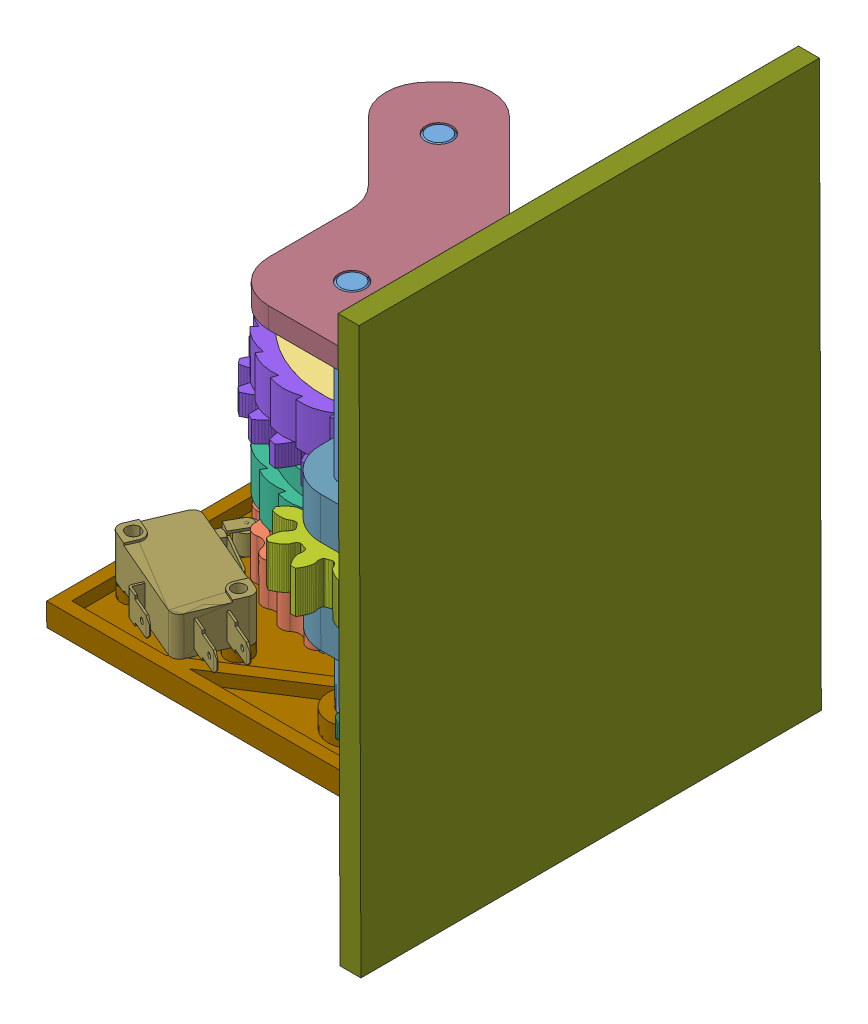
SolidWorks assembly Partially open assembly, configuration Default. Lengths in mm.
Overall size (104.96 135.58 125.24).
121 component instances, 25 part files, 36 mates.
Components (placement in the parent):
- Mounting bar-1: Mounting bar [Default] at (-40 -130.3709 9.0195) x (0.975852 0.000746 -0.218429) z (0.218431 -0.003332 0.975847) size (6.35 101.6 6.35)
- Mounting bar-2: Mounting bar [Default] at (-19.9279 -130.5102 49.7998) x (-0.610818 0.002704 -0.791767) z (0.791771 0.002086 -0.610814) size (6.35 101.6 6.35)
- Battery 9V-1: Battery 9V [Default] at (-16.7556 -79.5866 69.2456) x (1 0 0.000033) z (0.000033 0.003415 -0.999994) size (25.91 48.13 16.26) (hidden)
- Letter selection wheel assembly-1: Letter selection wheel assembly [Default] at (-83.764 -141.894 -21.2692) x (0.903739 0.001462 -0.428081) z (0.428084 -0.003086 0.903734) size (72.37 17.5 74.83)
  - Letter selection wheel-1: Letter selection wheel [Default] at (26.602 23.0199 46.072) size (64.18 15 64.19)
  - PCB assembly-1: PCB assembly [Default] at (20.8498 33.5038 101.5951) x (1 0 0) z (0 1 0) size (67.78 70.24 3.5)
    - selector wheel PCB-2: selector wheel PCB [Default] at (5.7522 55.5231 3.5161) size (67.78 70.24 1)
    - spring pin-27: spring pin [Default] at (7.3927 81.0239 5.3161) x (1 0 0) z (0 -1 0) size (3.66 2.5 0.96)
    - spring pin-28: spring pin [Default] at (1.2423 80.6755 5.3161) x (0.970942 0.239316 0) z (0.239316 -0.970942 0) size (3.66 2.5 0.96)
    - spring pin-29: spring pin [Default] at (-4.6461 78.8653 5.3161) x (0.885456 0.464723 0) z (0.464723 -0.885456 0) size (3.66 2.5 0.96)
    - spring pin-30: spring pin [Default] at (-9.9301 75.6986 5.3161) x (0.748511 0.663123 0) z (0.663123 -0.748511 0) size (3.66 2.5 0.96)
    - spring pin-31: spring pin [Default] at (-14.3027 71.3593 5.3161) x (0.568065 0.822984 0) z (0.822984 -0.568065 0) size (3.66 2.5 0.96)
    - spring pin-32: spring pin [Default] at (-17.5098 66.0997 5.3161) x (0.354605 0.935016 0) z (0.935016 -0.354605 0) size (3.66 2.5 0.96)
    - spring pin-33: spring pin [Default] at (-19.365 60.2254 5.3161) x (0.120537 0.992709 0) z (0.992709 -0.120537 0) size (3.66 2.5 0.96)
    - spring pin-34: spring pin [Default] at (-19.7605 54.0778 5.3161) x (-0.120537 0.992709 0) z (0.992709 0.120537 0) size (3.66 2.5 0.96)
    - spring pin-35: spring pin [Default] at (-18.6732 48.0142 5.3161) x (-0.354605 0.935016 0) z (0.935016 0.354605 0) size (3.66 2.5 0.96)
    - spring pin-36: spring pin [Default] at (-16.1665 42.3871 5.3161) x (-0.568065 0.822984 0) z (0.822984 0.568065 0) size (3.66 2.5 0.96)
    - spring pin-37: spring pin [Default] at (-12.3859 37.5233 5.3161) x (-0.748511 0.663123 0) z (0.663123 0.748511 0) size (3.66 2.5 0.96)
    - spring pin-38: spring pin [Default] at (-7.5512 33.7056 5.3161) x (-0.885456 0.464723 0) z (0.464723 0.885456 0) size (3.66 2.5 0.96)
    - spring pin-39: spring pin [Default] at (-1.9434 31.1559 5.3161) x (-0.970942 0.239316 0) z (0.239316 0.970942 0) size (3.66 2.5 0.96)
    - spring pin-40: spring pin [Default] at (4.1117 30.0223 5.3161) x (-1 0 0) z (0 1 0) size (3.66 2.5 0.96)
    - spring pin-41: spring pin [Default] at (10.2621 30.3707 5.3161) x (-0.970942 -0.239316 0) z (-0.239316 0.970942 0) size (3.66 2.5 0.96)
    - spring pin-42: spring pin [Default] at (16.1505 32.1809 5.3161) x (-0.885456 -0.464723 0) z (-0.464723 0.885456 0) size (3.66 2.5 0.96)
    - spring pin-43: spring pin [Default] at (21.4345 35.3476 5.3161) x (-0.748511 -0.663123 0) z (-0.663123 0.748511 0) size (3.66 2.5 0.96)
    - spring pin-44: spring pin [Default] at (25.8071 39.6869 5.3161) x (-0.568065 -0.822984 0) z (-0.822984 0.568065 0) size (3.66 2.5 0.96)
    - spring pin-45: spring pin [Default] at (29.0142 44.9465 5.3161) x (-0.354605 -0.935016 0) z (-0.935016 0.354605 0) size (3.66 2.5 0.96)
    - spring pin-46: spring pin [Default] at (30.8694 50.8208 5.3161) x (-0.120537 -0.992709 0) z (-0.992709 0.120537 0) size (3.66 2.5 0.96)
    - spring pin-47: spring pin [Default] at (31.2649 56.9684 5.3161) x (0.120537 -0.992709 0) z (-0.992709 -0.120537 0) size (3.66 2.5 0.96)
    - spring pin-48: spring pin [Default] at (30.1776 63.032 5.3161) x (0.354605 -0.935016 0) z (-0.935016 -0.354605 0) size (3.66 2.5 0.96)
    - spring pin-49: spring pin [Default] at (27.6709 68.6591 5.3161) x (0.568065 -0.822984 0) z (-0.822984 -0.568065 0) size (3.66 2.5 0.96)
    - spring pin-50: spring pin [Default] at (23.8903 73.5229 5.3161) x (0.748511 -0.663123 0) z (-0.663123 -0.748511 0) size (3.66 2.5 0.96)
    - spring pin-51: spring pin [Default] at (19.0556 77.3406 5.3161) x (0.885456 -0.464723 0) z (-0.464723 -0.885456 0) size (3.66 2.5 0.96)
    - spring pin-52: spring pin [Default] at (13.4478 79.8903 5.3161) x (0.970942 -0.239316 0) z (-0.239316 -0.970942 0) size (3.66 2.5 0.96)
  - selector wheel PCB-3: selector wheel PCB [Default] at (26.602 23.0199 46.072) x (1 0 0) z (0 1 0) size (67.78 70.24 1)
  - 57155K356 ball bearing-1: 57155K356 ball bearing [57155K356] at (26.602 31.4324 46.072) x (1 0 0) z (0 -1 0) size (12.7 12.7 3.17)
- Scrambler wheel assembly-1: Scrambler wheel assembly [Default] at (-30.9853 -125.6197 -45.8761) x (0.827018 -0.00192 0.562173) z (-0.562176 -0.002824 0.827013) size (72.54 17.5 74.67)
  - Scrambler wheel-1: Scrambler wheel [Default] at (23.4146 24.3298 50.4806) size (65.8 15 63.85)
  - PCB assembly-1: PCB assembly [Default] at (17.9086 34.8137 106.1338) x (1 0 0) z (0 1 0) size (67.78 70.24 3.5)
    - selector wheel PCB-2: selector wheel PCB [Default] at (5.7522 55.5231 3.5161) size (67.78 70.24 1)
    - spring pin-27: spring pin [Default] at (7.3927 81.0239 5.3161) x (1 0 0) z (0 -1 0) size (3.66 2.5 0.96)
    - spring pin-28: spring pin [Default] at (1.2423 80.6755 5.3161) x (0.970942 0.239316 0) z (0.239316 -0.970942 0) size (3.66 2.5 0.96)
    - spring pin-29: spring pin [Default] at (-4.6461 78.8653 5.3161) x (0.885456 0.464723 0) z (0.464723 -0.885456 0) size (3.66 2.5 0.96)
    - spring pin-30: spring pin [Default] at (-9.9301 75.6986 5.3161) x (0.748511 0.663123 0) z (0.663123 -0.748511 0) size (3.66 2.5 0.96)
    - spring pin-31: spring pin [Default] at (-14.3027 71.3593 5.3161) x (0.568065 0.822984 0) z (0.822984 -0.568065 0) size (3.66 2.5 0.96)
    - spring pin-32: spring pin [Default] at (-17.5098 66.0997 5.3161) x (0.354605 0.935016 0) z (0.935016 -0.354605 0) size (3.66 2.5 0.96)
    - spring pin-33: spring pin [Default] at (-19.365 60.2254 5.3161) x (0.120537 0.992709 0) z (0.992709 -0.120537 0) size (3.66 2.5 0.96)
    - spring pin-34: spring pin [Default] at (-19.7605 54.0778 5.3161) x (-0.120537 0.992709 0) z (0.992709 0.120537 0) size (3.66 2.5 0.96)
    - spring pin-35: spring pin [Default] at (-18.6732 48.0142 5.3161) x (-0.354605 0.935016 0) z (0.935016 0.354605 0) size (3.66 2.5 0.96)
    - spring pin-36: spring pin [Default] at (-16.1665 42.3871 5.3161) x (-0.568065 0.822984 0) z (0.822984 0.568065 0) size (3.66 2.5 0.96)
    - spring pin-37: spring pin [Default] at (-12.3859 37.5233 5.3161) x (-0.748511 0.663123 0) z (0.663123 0.748511 0) size (3.66 2.5 0.96)
    - spring pin-38: spring pin [Default] at (-7.5512 33.7056 5.3161) x (-0.885456 0.464723 0) z (0.464723 0.885456 0) size (3.66 2.5 0.96)
    - spring pin-39: spring pin [Default] at (-1.9434 31.1559 5.3161) x (-0.970942 0.239316 0) z (0.239316 0.970942 0) size (3.66 2.5 0.96)
    - spring pin-40: spring pin [Default] at (4.1117 30.0223 5.3161) x (-1 0 0) z (0 1 0) size (3.66 2.5 0.96)
    - spring pin-41: spring pin [Default] at (10.2621 30.3707 5.3161) x (-0.970942 -0.239316 0) z (-0.239316 0.970942 0) size (3.66 2.5 0.96)
    - spring pin-42: spring pin [Default] at (16.1505 32.1809 5.3161) x (-0.885456 -0.464723 0) z (-0.464723 0.885456 0) size (3.66 2.5 0.96)
    - spring pin-43: spring pin [Default] at (21.4345 35.3476 5.3161) x (-0.748511 -0.663123 0) z (-0.663123 0.748511 0) size (3.66 2.5 0.96)
    - spring pin-44: spring pin [Default] at (25.8071 39.6869 5.3161) x (-0.568065 -0.822984 0) z (-0.822984 0.568065 0) size (3.66 2.5 0.96)
    - spring pin-45: spring pin [Default] at (29.0142 44.9465 5.3161) x (-0.354605 -0.935016 0) z (-0.935016 0.354605 0) size (3.66 2.5 0.96)
    - spring pin-46: spring pin [Default] at (30.8694 50.8208 5.3161) x (-0.120537 -0.992709 0) z (-0.992709 0.120537 0) size (3.66 2.5 0.96)
    - spring pin-47: spring pin [Default] at (31.2649 56.9684 5.3161) x (0.120537 -0.992709 0) z (-0.992709 -0.120537 0) size (3.66 2.5 0.96)
    - spring pin-48: spring pin [Default] at (30.1776 63.032 5.3161) x (0.354605 -0.935016 0) z (-0.935016 -0.354605 0) size (3.66 2.5 0.96)
    - spring pin-49: spring pin [Default] at (27.6709 68.6591 5.3161) x (0.568065 -0.822984 0) z (-0.822984 -0.568065 0) size (3.66 2.5 0.96)
    - spring pin-50: spring pin [Default] at (23.8903 73.5229 5.3161) x (0.748511 -0.663123 0) z (-0.663123 -0.748511 0) size (3.66 2.5 0.96)
    - spring pin-51: spring pin [Default] at (19.0556 77.3406 5.3161) x (0.885456 -0.464723 0) z (-0.464723 -0.885456 0) size (3.66 2.5 0.96)
    - spring pin-52: spring pin [Default] at (13.4478 79.8903 5.3161) x (0.970942 -0.239316 0) z (-0.239316 -0.970942 0) size (3.66 2.5 0.96)
  - selector wheel PCB-1: selector wheel PCB [Default] at (23.4146 24.3298 50.4806) x (1 0 0) z (0 1 0) size (67.78 70.24 1)
  - 57155K356 ball bearing-1: 57155K356 ball bearing [57155K356] at (23.4146 35.9173 50.4806) x (1 0 0) z (0 -1 0) size (12.7 12.7 3.17)
- small gear-1: small gear [Default] at (-19.9279 -80.48 49.9706) x (-0.179158 0.003359 -0.983815) z (0 -0.999994 -0.003415) size (29.32 29.28 10)
- End cap wheel assembly-1: End cap wheel assembly [Default] at (-2.7358 -111.5836 -36.1506) x (0.398943 -0.003131 0.91697) z (-0.916976 -0.001362 0.398941) size (80.8 15 76.92)
  - endcap wheel-1: endcap wheel [Default] at (26.6122 32.7605 52.2161) size (68.11 15 68.39)
  - selector wheel PCB-1: selector wheel PCB [Default] at (26.8584 41.7605 52.3462) x (1 0 0) z (0 1 0) size (67.78 70.24 1)
  - selector wheel PCB-2: selector wheel PCB [Default] at (26.6122 28.7605 52.2161) x (-1 0 0) z (0 -1 0) size (67.78 70.24 1)
  - 57155K356 ball bearing-1: 57155K356 ball bearing [57155K356] at (26.6122 34.348 52.2161) x (-0.69888 0 -0.715239) z (0 -1 0) size (12.7 12.7 3.17)
- indication panel assembly-1: indication panel assembly [Default] at (-74.0802 -61.7764 -15.7084) x (1 0 0) z (0 -0.999994 -0.003415) size (80 81.5 28.5)
  - LED panel-1: LED panel [Default] at (34.0802 38.962 59.6162) size (80 80 28.5)
  - indication pcb assembly-1: indication pcb assembly [Default] at (55.4357 -6.4979 102.4788) x (-1 0 0) z (0 0 -1) size (55 56.48 3.5)
    - indication PCB-1: indication PCB [Default] at (21.3555 31.4598 41.8626) size (55 56.48 1)
    - spring pin-1: spring pin [Default] at (43.9085 31.3248 43.6626) x (0.090499 -0.995897 0) z (-0.995897 -0.090499 0) size (3.66 2.5 0.96)
    - spring pin-27: spring pin [Default] at (43.2208 25.9314 43.6626) x (-0.150465 -0.988615 0) z (-0.988615 0.150465 0) size (3.66 2.5 0.96)
    - spring pin-28: spring pin [Default] at (41.2624 20.8593 43.6626) x (-0.382683 -0.92388 0) z (-0.92388 0.382683 0) size (3.66 2.5 0.96)
    - spring pin-29: spring pin [Default] at (38.1471 16.4033 43.6626) x (-0.592662 -0.805451 0) z (-0.805451 0.592662 0) size (3.66 2.5 0.96)
    - spring pin-30: spring pin [Default] at (34.0559 12.8224 43.6626) x (-0.768198 -0.640213 0) z (-0.640213 0.768198 0) size (3.66 2.5 0.96)
    - spring pin-31: spring pin [Default] at (29.2266 10.3245 43.6626) x (-0.899088 -0.437768 0) z (-0.437768 0.899088 0) size (3.66 2.5 0.96)
    - spring pin-32: spring pin [Default] at (23.9398 9.055 43.6626) x (-0.977727 -0.209881 0) z (-0.209881 0.977727 0) size (3.66 2.5 0.96)
    - spring pin-33: spring pin [Default] at (18.5029 9.0876 43.6626) x (-0.999544 0.030203 0) z (0.030203 0.999544 0) size (3.66 2.5 0.96)
    - spring pin-34: spring pin [Default] at (13.2318 10.4204 43.6626) x (-0.963271 0.268532 0) z (0.268532 0.963271 0) size (3.66 2.5 0.96)
    - spring pin-35: spring pin [Default] at (8.4328 12.9759 43.6626) x (-0.871016 0.491255 0) z (0.491255 0.871016 0) size (3.66 2.5 0.96)
    - spring pin-36: spring pin [Default] at (4.3848 16.6056 43.6626) x (-0.728141 0.685427 0) z (0.685427 0.728141 0) size (3.66 2.5 0.96)
    - spring pin-37: spring pin [Default] at (1.323 21.0986 43.6626) x (-0.542949 0.839766 0) z (0.839766 0.542949 0) size (3.66 2.5 0.96)
    - spring pin-38: spring pin [Default] at (-0.5745 26.1937 43.6626) x (-0.326203 0.9453 0) z (0.9453 0.326203 0) size (3.66 2.5 0.96)
    - spring pin-39: spring pin [Default] at (-1.1975 31.5949 43.6626) x (-0.090499 0.995897 0) z (0.995897 0.090499 0) size (3.66 2.5 0.96)
    - spring pin-40: spring pin [Default] at (-0.5098 36.9883 43.6626) x (0.150465 0.988615 0) z (0.988615 -0.150465 0) size (3.66 2.5 0.96)
    - spring pin-41: spring pin [Default] at (1.4486 42.0604 43.6626) x (0.382683 0.92388 0) z (0.92388 -0.382683 0) size (3.66 2.5 0.96)
    - spring pin-42: spring pin [Default] at (4.5639 46.5163 43.6626) x (0.592662 0.805451 0) z (0.805451 -0.592662 0) size (3.66 2.5 0.96)
    - spring pin-43: spring pin [Default] at (8.6551 50.0973 43.6626) x (0.768198 0.640213 0) z (0.640213 -0.768198 0) size (3.66 2.5 0.96)
    - spring pin-44: spring pin [Default] at (13.4844 52.5951 43.6626) x (0.899088 0.437768 0) z (0.437768 -0.899088 0) size (3.66 2.5 0.96)
    - spring pin-45: spring pin [Default] at (18.7711 53.8647 43.6626) x (0.977727 0.209881 0) z (0.209881 -0.977727 0) size (3.66 2.5 0.96)
    - spring pin-46: spring pin [Default] at (24.208 53.8321 43.6626) x (0.999544 -0.030203 0) z (-0.030203 -0.999544 0) size (3.66 2.5 0.96)
    - spring pin-47: spring pin [Default] at (29.4792 52.4993 43.6626) x (0.963271 -0.268532 0) z (-0.268532 -0.963271 0) size (3.66 2.5 0.96)
    - spring pin-48: spring pin [Default] at (34.2782 49.9438 43.6626) x (0.871016 -0.491255 0) z (-0.491255 -0.871016 0) size (3.66 2.5 0.96)
    - spring pin-49: spring pin [Default] at (38.3262 46.3141 43.6626) x (0.728141 -0.685427 0) z (-0.685427 -0.728141 0) size (3.66 2.5 0.96)
    - spring pin-50: spring pin [Default] at (41.3879 41.8211 43.6626) x (0.542949 -0.839766 0) z (-0.839766 -0.542949 0) size (3.66 2.5 0.96)
    - spring pin-51: spring pin [Default] at (43.2854 36.726 43.6626) x (0.326203 -0.9453 0) z (-0.9453 -0.326203 0) size (3.66 2.5 0.96)
    - spring pin-52: spring pin [Default] at (21.7527 46.348 43.6626) x (1 0 0) z (0 -1 0) size (3.66 2.5 0.96)
- ball bearing - small-1: ball bearing - small [57155K356] at (-19.9279 -85.48 49.9536) x (1 0 -0.00001) z (0 -0.999994 -0.003415) size (12.7 12.7 3.17)
- 7779K420 ball switch-1: 7779K420 ball switch [Default] at (-61.5653 -113.4562 48.2145) x (0.919055 -0.001346 0.394127) z (0 0.999994 0.003415) size (37.8 27.88 10.31)
- 57155K356 ball bearing-1: 57155K356 ball bearing [57155K356] at (-19.9279 -82.0675 49.9652) x (0.999712 -0.000082 0.024004) z (0 0.999994 0.003415) size (12.7 12.7 3.17)
- Leg-1: Leg [Default] at (0.0021 -33.8782 40.6145) x (0 0.999994 0.003415) z (0 -0.003415 0.999994) size (18 54.87 70.66)
- Ratcheters-1: Ratcheters [Default] at (0.0021 -78.9512 10.2493) x (0 0.003415 -0.999994) z (0 0.999994 0.003415) size (20.21 29.93 10)
- Ratcheters-3: Ratcheters [Default] at (0.0021 -101.4092 10.1726) x (0 0.003415 -0.999994) z (0 0.999994 0.003415) size (20.21 29.93 10)
- Button leg-1: Button leg [Default] at (0.0021 -91.5714 57.6747) x (0 -0.999994 -0.003415) z (-1 0 0) size (15 60.42 5.93)
- base-1: base [Default] at (10 -76.4223 23.2038) x (0 0.999994 0.003415) z (0 -0.003415 0.999994) size (135.21 10 110)
- ESE18R11B limit switch-1: ESE18R11B limit switch [Default] at (-4 -95.4347 -3.4249) x (1 0 0) z (0 -0.999994 -0.003415) size (4.53 6.66 1.63)
  - sw-131-e18lv3-sk-1-1: sw-131-e18lv3-sk-1 [Default] at (0 1.7032 0.705) x (0.610145 0.79229 0) z (0 0 1) size (3.45 1.75 1)
  - sw-131-e18fm4-sk-1-1: sw-131-e18fm4-sk-1 [Default] at (0 4.5758 1.23) size (4 4.4 1.2)
  - sw-131-e18ts-j-sk-1-1: sw-131-e18ts-j-sk-1 [Default] at (0 0.0532 0) size (0.44 0.5 0.5)
  - sw-131-e18ts-j-sk-1_2-1: sw-131-e18ts-j-sk-1_2 [Default] at (0 0.0532 0) size (0.44 0.5 0.5)
  - sw-131-e18ts-j-sk-1_3-1: sw-131-e18ts-j-sk-1_3 [Default] at (0 0.0532 0) size (0.5 0.44 0.5)
  - sw-131-e18ts-j-sk-1_4-1: sw-131-e18ts-j-sk-1_4 [Default] at (0 0.0532 0) size (0.5 0.44 0.5)
  - sw-131-e18cs-boss-pc-1-1: sw-131-e18cs-boss-pc-1 [Default] at origin size (4 4.5 1.53)
- limit switch holder-1: limit switch holder [Default] at (0 -95.4407 -1.6718) x (0 0.003415 -0.999994) z (0 0.999994 0.003415) size (10 6 10)
Mates (geometry in assembly coordinates):
- Coincident3: coincident: plane of Mounting bar-1 through (-40 -28.7715 9.3664) normal (0 0.999994 0.003415); plane of Mounting bar-2 through (-19.9279 -28.9108 50.1467) normal (0 0.999994 0.003415)
- Concentric7: concentric aligned: cylinder of Mounting bar-1 through (-40 -28.7715 9.3664) axis (0 -0.999994 -0.003415) radius 3.175; circle of Letter selection wheel assembly-1/57155K356 ball bearing-1
- Concentric8: concentric aligned: cylinder of Mounting bar-1 through (-40 -28.7715 9.3664) axis (0 -0.999994 -0.003415) radius 3.175; circle of Scrambler wheel assembly-1/57155K356 ball bearing-1
- Concentric10: concentric anti-aligned: cylinder of Mounting bar-2 through (-19.9279 -28.9108 50.1467) axis (0 -0.999994 -0.003415) radius 3.175; cylinder of small gear-1 through (-19.9279 -90.4799 49.9365) axis (0 0.999994 0.003415) radius 6.35
- Coincident9: coincident: line of Letter selection wheel assembly-1/PCB assembly-1/spring pin-49 through (-26.2734 -101.4041 -12.4016) axis (-0.500583 -0.002956 0.865683); plane of Scrambler wheel assembly-1/selector wheel PCB-1 through (-40 -101.4776 9.1182) normal (0 -0.999994 -0.003415)
- Concentric11: concentric aligned: cylinder of Mounting bar-1 through (-40 -28.7715 9.3664) axis (0 -0.999994 -0.003415) radius 3.175; circle of End cap wheel assembly-1/57155K356 ball bearing-1
- Coincident12: coincident: line of Scrambler wheel assembly-1/PCB assembly-1/spring pin-50 through (-15.7862 -83.9619 4.5542) axis (0.969209 0.000841 -0.246238); plane of End cap wheel assembly-1/selector wheel PCB-2 through (-40 -83.9777 9.1779) normal (0 -0.999994 -0.003415)
- Coincident32: coincident: plane of Letter selection wheel assembly-1/selector wheel PCB-3 through (-40 -118.9775 9.0584) normal (0 -0.999994 -0.003415); moEndPointRef_w of indication panel assembly-1/indication pcb assembly-1/spring pin-46
- Concentric12: concentric: cylinder of Mounting bar-1 through (-40 -28.7715 9.3664) axis (0 -0.999994 -0.003415) radius 3.175; circle of indication panel assembly-1/LED panel-1
- Concentric13: concentric anti-aligned: cylinder of small gear-1 through (-19.9279 -90.4799 49.9365) axis (0 0.999994 0.003415) radius 6.35; cylinder of ball bearing - small-1 through (-19.9279 -87.0674 49.9481) axis (0 -0.999994 -0.003415) radius 6.35
- Width1: width aligned: plane of small gear-1 through (-19.9279 -80.48 49.9706) normal (0 0.999994 0.003415); plane of small gear-1 through (-19.9279 -90.4799 49.9365) normal (0 -0.999994 -0.003415); plane of ball bearing - small-1 through (-19.9278 -83.9136 56.1502) normal (0 0.999994 0.003415); plane of ball bearing - small-1 through (-19.9278 -87.0886 56.1394) normal (0 -0.999994 -0.003415)
- Distance1: distance = 5 mm anti-aligned: plane of Battery 9V-1 through (-26.9202 -116.646 58.4175) normal (0 -0.999994 -0.003415); plane of indication panel assembly-1/LED panel-1 through (-40 -121.5253 23.0498) normal (0 0.999994 0.003415)
- Coincident62: coincident: plane of indication panel assembly-1/LED panel-1 through (-40 -118.5253 23.06) normal (0 0.999994 0.003415); plane of 7779K420 ball switch-1 through (-77.4735 -118.6174 50.025) normal (0 -0.999994 -0.003415)
- Coincident63: coincident: line of Letter selection wheel assembly-1/Letter selection wheel-1 through (-64.2197 -109.045 28.84) axis (0 -0.999994 -0.003415); cylinder of 7779K420 ball switch-1 through (-64.0702 -110.9982 31.2287) axis (0 -0.999994 -0.003415) radius 2.4
- Concentric16: concentric aligned: cylinder of small gear-1 through (-19.9279 -90.4799 49.9365) axis (0 0.999994 0.003415) radius 6.35; cylinder of 57155K356 ball bearing-1 through (-19.9279 -80.48 49.9706) axis (0 0.999994 0.003415) radius 6.35
- Coincident64: coincident aligned: plane of small gear-1 through (-19.9279 -80.48 49.9706) normal (0 0.999994 0.003415); plane of 57155K356 ball bearing-1 through (-19.7793 -80.4588 43.7812) normal (0 0.999994 0.003415)
- Coincident65: coincident: line of Letter selection wheel assembly-1/Letter selection wheel-1 through (-61.7086 -109.0546 31.663) axis (0 -0.999994 -0.003415); cylinder of 7779K420 ball switch-1 through (-64.0702 -110.9982 31.2287) axis (0 -0.999994 -0.003415) radius 2.4
- Concentric17: concentric aligned: cylinder of Mounting bar-2 through (-19.9279 -28.9108 50.1467) axis (0 -0.999994 -0.003415) radius 3.175; cylinder of Leg-1 through (-19.9279 -28.9108 50.1467) axis (0 -0.999994 -0.003415) radius 3.175
- Parallel4: parallel aligned: plane of indication panel assembly-1/LED panel-1 through (0 -124.1619 63.041) normal (1 0 0); plane of Leg-1 through (0.0021 -28.8506 32.5173) normal (1 0 0)
- Coincident67: coincident aligned: plane of Mounting bar-2 through (-19.9279 -28.9108 50.1467) normal (0 0.999994 0.003415); plane of Leg-1 through (-24.8967 -28.9278 55.1467) normal (0 0.999994 0.003415)
- Concentric19: concentric aligned: cylinder of Mounting bar-2 through (-19.9279 -28.9108 50.1467) axis (0 -0.999994 -0.003415) radius 3.175; cylinder of Ratcheters-1 through (-19.9279 -69.0869 50.0095) axis (0 -0.999994 -0.003415) radius 3.175
- Parallel5: parallel aligned: plane of Leg-1 through (0.0021 -28.8506 32.5173) normal (1 0 0); plane of Ratcheters-1 through (0.0021 -69.0605 42.2715) normal (1 0 0)
- Parallel6: parallel aligned: plane of indication panel assembly-1/LED panel-1 through (0 -124.1619 63.041) normal (1 0 0); plane of Ratcheters-3 through (0.0021 -91.5185 42.1948) normal (1 0 0)
- Concentric22: concentric aligned: cylinder of Mounting bar-2 through (-19.9279 -28.9108 50.1467) axis (0 -0.999994 -0.003415) radius 3.175; cylinder of Ratcheters-3 through (-19.9279 -91.5449 49.9329) axis (0 -0.999994 -0.003415) radius 3.175
- Coincident72: coincident anti-aligned: plane of Ratcheters-3 through (0.0021 -91.5185 42.1948) normal (0 0.003415 -0.999994); plane of Button leg-1 through (-4.9979 -101.5185 42.1607) normal (0 -0.003415 0.999994)
- Coincident73: coincident aligned: plane of Ratcheters-3 through (0.0021 -91.5185 42.1948) normal (1 0 0); plane of Button leg-1 through (0.0021 -91.5714 57.6747) normal (1 0 0)
- Coincident74: coincident anti-aligned: plane of Ratcheters-3 through (-19.9279 -101.5372 47.6368) normal (0 -0.999994 -0.003415); plane of Button leg-1 through (-4.9979 -101.6123 69.6405) normal (0 0.999994 0.003415)
- Coincident76: coincident: plane of indication panel assembly-1/LED panel-1 through (0 -124.1619 63.041) normal (1 0 0); plane of assembly through (0 0 0) normal (1 0 0)
- Coincident77: coincident anti-aligned: plane of indication panel assembly-1/LED panel-1 through (0 -124.1619 63.041) normal (1 0 0); plane of base-1 through (0 -76.4223 23.2038) normal (-1 0 0)
- Width2: width anti-aligned: plane of base-1 through (0 -143.8391 -32.0267) normal (0 -0.999994 -0.003415); plane of base-1 through (0 -8.6299 -31.565) normal (0 0.999994 0.003415); plane of Leg-1 through (-24.8967 -28.9278 55.1467) normal (0 0.999994 0.003415); plane of indication panel assembly-1/LED panel-1 through (-40 -124.0253 23.0412) normal (0 -0.999994 -0.003415)
- Width3: width aligned: plane of base-1 through (0 -144.2147 77.9726) normal (0 -0.003415 0.999994); plane of base-1 through (0 -143.8391 -32.0267) normal (0 0.003415 -0.999994); plane of indication panel assembly-1/LED panel-1 through (-80 -124.1619 63.041) normal (0 -0.003415 0.999994); plane of indication panel assembly-1/LED panel-1 through (-80 -123.8887 -16.9585) normal (0 0.003415 -0.999994)
- Coincident78: coincident anti-aligned: plane of indication panel assembly-1/LED panel-1 through (-40 -95.5255 23.1386) normal (0 0.999994 0.003415); plane of limit switch holder-1 through (0 -95.4066 -11.6717) normal (0 -0.999994 -0.003415)
- Coincident79: coincident anti-aligned: plane of base-1 through (0 -76.4223 23.2038) normal (-1 0 0); plane of limit switch holder-1 through (0 -85.4066 -11.6376) normal (1 0 0)
- Coincident80: coincident anti-aligned: plane of ESE18R11B limit switch-1/sw-131-e18cs-boss-pc-1-1 through (-4 -95.4266 -5.8217) normal (0 0.999994 0.003415); plane of limit switch holder-1 through (0 -95.4066 -11.6717) normal (0 -0.999994 -0.003415)
- Distance3: distance = 2 mm anti-aligned: plane of base-1 through (0 -76.4223 23.2038) normal (-1 0 0); plane of ESE18R11B limit switch-1/sw-131-e18cs-boss-pc-1-1 through (-2 -96.5566 -5.8256) normal (1 0 0)
- Coincident85: coincident aligned: plane of ESE18R11B limit switch-1/sw-131-e18cs-boss-pc-1-1 through (-6 -96.5707 -1.6756) normal (0 -0.003415 0.999994); plane of limit switch holder-1 through (0 -95.4407 -1.6718) normal (0 -0.003415 0.999994)
